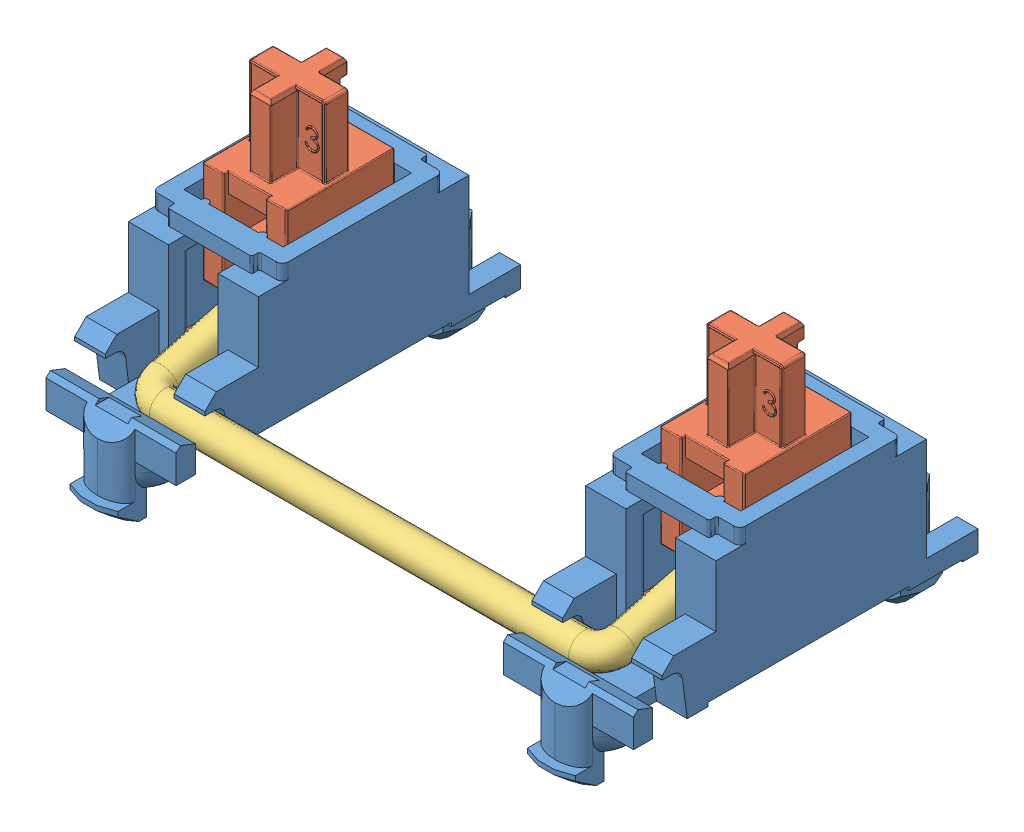
SolidWorks assembly Cherry MX Stabilizer, configuration Default. Lengths in mm.
Overall size (30.7 14.96 19.2).
5 component instances, 3 part files, 8 mates.
Components (placement in the parent):
- mx Stabilizer base 16828-1: mx Stabilizer base 16828 [Default] at origin size (6.8 10.1 19.2)
- mx Stabilizer key 16828-1: mx Stabilizer key 16828 [Default] at (0 4.757 0) size (4.41 11.95 8.3)
- metal stick 16828-1: metal stick 16828 [Default] at (11.95 0.6706 -3.0582) x (1 0 0) z (0 -0.243034 0.970018) size (25.5 1.6 12.2)
- mx Stabilizer base 16828-2: mx Stabilizer base 16828 [Default] at (23.9 0 0) size (6.8 10.1 19.2)
- mx Stabilizer key 16828-2: mx Stabilizer key 16828 [Default] at (23.9 4.757 0) size (4.41 11.95 8.3)
Mates (geometry in assembly coordinates):
- Coincident1: coincident aligned: plane of mx Stabilizer key 16828-1 through (0 4.757 0) normal (1 0 0); plane of assembly through (0 0 0) normal (1 0 0)
- Coincident2: coincident aligned: plane of mx Stabilizer key 16828-1 through (0 4.757 0) normal (0 0 1); plane of assembly through (0 0 0) normal (0 0 1)
- Coincident3: coincident aligned: plane of metal stick 16828-1; plane of assembly through (0 0 0) normal (1 0 0)
- Tangent1: tangent anti-aligned: plane of mx Stabilizer base 16828-1 through (0 -2.9 10.5) normal (0 1 0); cylinder of metal stick 16828-1 through (22.9 -2.1 8) axis (-1 0 0) radius 0.8
- Tangent2: tangent anti-aligned: plane of mx Stabilizer base 16828-1 through (3.4 -3.6 8.8) normal (0 0 -1); cylinder of metal stick 16828-1 through (22.9 -2.1 8) axis (-1 0 0) radius 0.8
- Tangent3: tangent: line of mx Stabilizer key 16828-1 through (-1.1 0.757 -0.1115) axis (1 0 0); cylinder of metal stick 16828-1 through (0 -1.857 7.03) axis (0 0.243034 -0.970018) radius 0.8
- LimitDistance1: limit distance = 3.343 mm anti-aligned: plane of mx Stabilizer base 16828-1 through (3.4 2.1 5.5) normal (0 -1 0); plane of mx Stabilizer key 16828-1 through (0 -1.243 0) normal (0 1 0)
- LimitDistance2: limit distance = 0.107 mm aligned: plane of mx Stabilizer key 16828-1 through (0.45 -3.493 -3.8) normal (0 -1 0); plane of mx Stabilizer base 16828-1 through (3.4 -3.6 -4.6) normal (0 -1 0)
